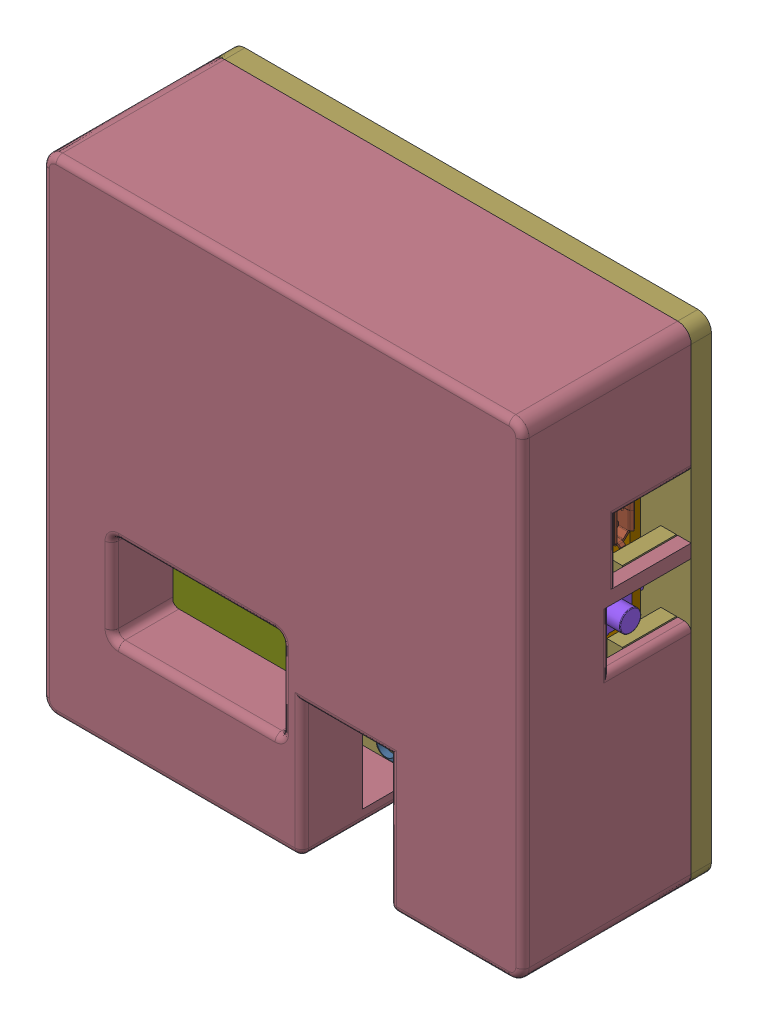
SolidWorks assembly Montagem Oximetro, configuration Valor predeterminado. Lengths in mm.
Overall size (71.15 72 28).
84 component instances, 29 part files, 20 mates.
Components (placement in the parent):
- ESP32-devkit_v1.step-1: ESP32-devkit_v1.step [Valor predeterminado] at (96.8522 -59.7162 9.78) x (0 -1 0) z (0 0 1) size (28.3 51.77 12.9)
  - ____________________ __________.step-1: ____________________ __________.step [Valor predeterminado] at origin size (27.94 38.1 11.2)
    - Body001.step-1: Body001.step [Valor predeterminado] at origin size (2.54 2.54 11.2)
    - Body001.step-2: Body001.step [Valor predeterminado] at (0 2.54 0) size (2.54 2.54 11.2)
    - Body001.step-3: Body001.step [Valor predeterminado] at (0 5.08 0) size (2.54 2.54 11.2)
    - Body001.step-4: Body001.step [Valor predeterminado] at (0 7.62 0) size (2.54 2.54 11.2)
    - Body001.step-5: Body001.step [Valor predeterminado] at (0 10.16 0) size (2.54 2.54 11.2)
    - Body001.step-6: Body001.step [Valor predeterminado] at (0 12.7 0) size (2.54 2.54 11.2)
    - Body001.step-7: Body001.step [Valor predeterminado] at (0 15.24 0) size (2.54 2.54 11.2)
    - Body001.step-8: Body001.step [Valor predeterminado] at (0 17.78 0) size (2.54 2.54 11.2)
    - Body001.step-9: Body001.step [Valor predeterminado] at (0 20.32 0) size (2.54 2.54 11.2)
    - Body001.step-10: Body001.step [Valor predeterminado] at (0 22.86 0) size (2.54 2.54 11.2)
    - Body001.step-11: Body001.step [Valor predeterminado] at (0 25.4 0) size (2.54 2.54 11.2)
    - Body001.step-12: Body001.step [Valor predeterminado] at (0 27.94 0) size (2.54 2.54 11.2)
    - Body001.step-13: Body001.step [Valor predeterminado] at (0 30.48 0) size (2.54 2.54 11.2)
    - Body001.step-14: Body001.step [Valor predeterminado] at (0 33.02 0) size (2.54 2.54 11.2)
    - Body001.step-15: Body001.step [Valor predeterminado] at (0 35.56 0) size (2.54 2.54 11.2)
    - Body001.step-16: Body001.step [Valor predeterminado] at (25.4 0 0) size (2.54 2.54 11.2)
    - Body001.step-17: Body001.step [Valor predeterminado] at (25.4 2.54 0) size (2.54 2.54 11.2)
    - Body001.step-18: Body001.step [Valor predeterminado] at (25.4 5.08 0) size (2.54 2.54 11.2)
    - Body001.step-19: Body001.step [Valor predeterminado] at (25.4 7.62 0) size (2.54 2.54 11.2)
    - Body001.step-20: Body001.step [Valor predeterminado] at (25.4 10.16 0) size (2.54 2.54 11.2)
    - Body001.step-21: Body001.step [Valor predeterminado] at (25.4 12.7 0) size (2.54 2.54 11.2)
    - Body001.step-22: Body001.step [Valor predeterminado] at (25.4 15.24 0) size (2.54 2.54 11.2)
    - Body001.step-23: Body001.step [Valor predeterminado] at (25.4 17.78 0) size (2.54 2.54 11.2)
    - Body001.step-24: Body001.step [Valor predeterminado] at (25.4 20.32 0) size (2.54 2.54 11.2)
    - Body001.step-25: Body001.step [Valor predeterminado] at (25.4 22.86 0) size (2.54 2.54 11.2)
    - Body001.step-26: Body001.step [Valor predeterminado] at (25.4 25.4 0) size (2.54 2.54 11.2)
    - Body001.step-27: Body001.step [Valor predeterminado] at (25.4 27.94 0) size (2.54 2.54 11.2)
    - Body001.step-28: Body001.step [Valor predeterminado] at (25.4 30.48 0) size (2.54 2.54 11.2)
    - Body001.step-29: Body001.step [Valor predeterminado] at (25.4 33.02 0) size (2.54 2.54 11.2)
    - Body001.step-30: Body001.step [Valor predeterminado] at (25.4 35.56 0) size (2.54 2.54 11.2)
  - ________________ __________.step-1: ________________ __________.step [Valor predeterminado] at origin size (28.3 51.2 1.6)
  - ESP32-WROOM-32.step-1: ESP32-WROOM-32.step [Valor predeterminado] at (14 15.8 1.6) x (-1 0 0) z (0 0 1) size (18 25.5 3.1)
  - USB_Micro-B_Molex_47346-0001.step-1: USB_Micro-B_Molex_47346-0001.step [Valor predeterminado] at (14 48 1.6) x (-1 0 0) z (0 0 1) size (7.98 5.42 2.97)
  - AMS-1117.step-1: AMS-1117.step [Valor predeterminado] at (19.5 39.6 1.6) size (7 6.5 1.7)
  - cp2102.step-1: cp2102.step [Valor predeterminado] at (8.2 39.5 1.6) x (-1 0 0) z (0 0 1) size (5 5 0.92)
  - SOT_23-1.step-1: SOT_23-1.step [Valor predeterminado] at (8 33.6 1.6) size (2.5 3 1.2)
  - SOT_23-2.step-1: SOT_23-2.step [Valor predeterminado] at (13.6 33.6 1.6) x (-1 0 0) z (0 0 1) size (2.5 3 1.2)
  - SW_SPST_B3U-1000P-1.step-1: SW_SPST_B3U-1000P-1.step [Valor predeterminado] at (6.2 48 1.6) x (0 1 0) z (0 0 1) size (4 2.51 1.59)
  - SW_SPST_B3U-1000P-2.step-1: SW_SPST_B3U-1000P-2.step [Valor predeterminado] at (22.2 48 1.6) x (0 1 0) z (0 0 1) size (4 2.51 1.59)
  - CP_EIA_3216_10_Kemet_I.step-1: CP_EIA_3216_10_Kemet_I.step [Valor predeterminado] at (21 34.2 1.6) x (-1 0 0) z (0 0 1) size (3.4 1.8 1.2)
- Case Montagem-1: Case Montagem [Valor predeterminado] at (126.0249 -86.5999 -4.5) x (1 0 0) z (0 -1 0) size (71.15 25 72)
  - Tampa Oximetro-1: Tampa Oximetro [Valor predeterminado] at origin size (71.15 11 72)
  - Case Oximetro-1: Case Oximetro [Valor predeterminado] at (0 25 0) x (1 0 0) z (0 0 -1) size (71.15 25 72)
  - IS - DIN985_M03×0.50-1: IS - DIN985_M03×0.50 [Valor predeterminado] at (-27.075 17.5 -0.5) size (6.08 4.25 5.5)
- pan head cross recess screw_iso-6: pan head cross recess screw_iso [ISO 7045 - M3 x 16 - Z - 16N] at (99.0249 -86.1024 -2.4) x (0 0 1) z (-1 0 0) size (18.35 5.6 5.6)
- pan head cross recess screw_iso-7: pan head cross recess screw_iso [ISO 7045 - M3 x 16 - Z - 16N] at (99.0249 -61.5924 -2.4) x (0 0 1) z (-1 0 0) size (18.35 5.6 5.6)
- pan head cross recess screw_iso-8: pan head cross recess screw_iso [ISO 7045 - M3 x 16 - Z - 16N] at (145.9749 -86.1024 -2.4) x (0 0 1) z (-1 0 0) size (18.35 5.6 5.6)
- pan head cross recess screw_iso-9: pan head cross recess screw_iso [ISO 7045 - M3 x 16 - Z - 16N] at (145.9749 -61.5924 -2.4) x (0 0 1) z (-1 0 0) size (18.35 5.6 5.6)
- 0.96 - IPS LCD - ST7735S.stp-1: 0.96 - IPS LCD - ST7735S.stp [Valor predeterminado] at (111.7844 -101.8949 9.78) size (31.02 24.13 4.17)
- pan head cross recess screw_iso-12: pan head cross recess screw_iso [ISO 7045 - M2 x 8 - Z - 8N] at (124.3955 -111.5215 8.18) x (0 0 1) z (-1 0 0) size (9.57 4 4)
- pan head cross recess screw_iso-13: pan head cross recess screw_iso [ISO 7045 - M2 x 8 - Z - 8N] at (99.1733 -111.5215 8.18) x (0 0 1) z (-1 0 0) size (9.57 4 4)
- pan head cross recess screw_iso-14: pan head cross recess screw_iso [ISO 7045 - M2 x 8 - Z - 8N] at (99.1733 -92.2683 8.18) x (0 0 1) z (-1 0 0) size (9.57 4 4)
- pan head cross recess screw_iso-15: pan head cross recess screw_iso [ISO 7045 - M2 x 8 - Z - 8N] at (124.3955 -92.2683 8.18) x (0 0 1) z (-1 0 0) size (9.57 4 4)
- hex thin nut chamfered gradeab_iso-4: hex thin nut chamfered gradeab_iso [ISO - 4035 - M2 - N] at (124.3955 -111.5215 13) x (0.866025 -0.5 0) z (0 0 -1) size (4 4.62 1.2)
- PCB_Oximetro.step-2: PCB_Oximetro.step [Valor predeterminado] at origin size (64.85 57.9 12.09)
  - CP_Radial_D5.0mm_P2.50mm.step-1: CP_Radial_D5.0mm_P2.50mm.step [Valor predeterminado] at (135.9499 -67.0499 1.63) size (6.13 6.52 7)
    - SOLID.step-1: SOLID.step [Valor predeterminado] at origin size (6.13 6.52 7)
  - PinSocket_1x08_P2.54mm_Vertical.step-1: PinSocket_1x08_P2.54mm_Vertical.step [Valor predeterminado] at (102.8999 -91.2999 1.63) x (0 1 0) z (0 0 1) size (2.54 20.32 10.1)
    - SOLID-0.step-1: SOLID-0.step [Valor predeterminado] at origin size (2.54 20.32 10.1)
  - SOT-223.step-1: SOT-223.step [Valor predeterminado] at (150.1499 -104.1999 1.63) x (0 -1 0) z (0 0 1) size (7 6.5 1.7)
    - SOLID-1.step-1: SOLID-1.step [Valor predeterminado] at origin size (7 6.5 1.7)
  - CP_Radial_Tantal_D5.0mm_P2.50mm.step-1: CP_Radial_Tantal_D5.0mm_P2.50mm.step [Valor predeterminado] at (148.9348 -110.8948 1.63) x (0 -1 0) z (0 0 1) size (5 5 10.1)
    - SOLID-2.step-1: SOLID-2.step [Valor predeterminado] at origin size (5 5 10.1)
  - CP_Radial_D5.0mm_P2.50mm.step-2: CP_Radial_D5.0mm_P2.50mm.step [Valor predeterminado] at (148.8999 -94.3499 1.63) size (6.13 6.52 7)
    - SOLID.step-1: SOLID.step [Valor predeterminado] at origin size (6.13 6.52 7)
  - R_1206_3216Metric.step-1: R_1206_3216Metric.step [Valor predeterminado] at (137.3499 -71.7999 1.63) size (3.2 1.6 0.55)
    - SOLID-3.step-1: SOLID-3.step [Valor predeterminado] at origin size (3.2 1.6 0.55)
  - PinSocket_1x05_P2.54mm_Vertical.step-1: PinSocket_1x05_P2.54mm_Vertical.step [Valor predeterminado] at (139.9999 -103.1999 1.63) x (0 -1 0) z (0 0 1) size (2.54 12.7 10.1)
    - SOLID-4.step-1: SOLID-4.step [Valor predeterminado] at origin size (2.54 12.7 10.1)
  - C_1206_3216Metric.step-1: C_1206_3216Metric.step [Valor predeterminado] at (153.2499 -111.1499 1.63) x (0 -1 0) z (0 0 1) size (3.2 1.6 1.6)
    - SOLID-5.step-1: SOLID-5.step [Valor predeterminado] at origin size (3.2 1.6 1.6)
  - C_1206_3216Metric.step-2: C_1206_3216Metric.step [Valor predeterminado] at (150.1499 -98.4999 1.63) size (3.2 1.6 1.6)
    - SOLID-5.step-1: SOLID-5.step [Valor predeterminado] at origin size (3.2 1.6 1.6)
  - D_DO-41_SOD81_P10.16mm_Horizontal.step-1: D_DO-41_SOD81_P10.16mm_Horizontal.step [Valor predeterminado] at (139.8199 -77.6999 1.63) size (10.96 2.72 5.71)
    - SOLID-6.step-1: SOLID-6.step [Valor predeterminado] at origin size (10.96 2.72 5.71)
  - SW_Tactile_SPST_Angled_PTS645Vx58-2LFS.step-1: SW_Tactile_SPST_Angled_PTS645Vx58-2LFS.step [Valor predeterminado] at (155.0374 -82.2249 1.63) x (0 -1 0) z (0 0 1) size (7.4 9.9 11)
    - SOLID-7.step-1: SOLID-7.step [Valor predeterminado] at origin size (7.4 9.9 11)
  - R_1206_3216Metric.step-2: R_1206_3216Metric.step [Valor predeterminado] at (149.3999 -83.7124 1.63) x (0 1 0) z (0 0 1) size (3.2 1.6 0.55)
    - SOLID-3.step-1: SOLID-3.step [Valor predeterminado] at origin size (3.2 1.6 0.55)
  - PCB.step-1: PCB.step [Valor predeterminado] at origin size (61.2 57.9 1.58)
- MAX30102-1: MAX30102 [Default] at (135.2675 -107.9442 10.38) x (1 0 0) z (0 -1 0) size (12 1.84 12)
- Micro USB 5 Pins, Right Angle SMT-1: Micro USB 5 Pins, Right Angle SMT [Default] at (157.0999 -73.6478 2.805) x (0 1 0) z (1 0 0) size (8.07 3.21 5.56)
Mates (geometry in assembly coordinates):
- Coincidente24: coincident: plane of ESP32-devkit_v1.step-1/________________ __________.step-1 through (122.4522 -73.8662 9.78) normal (0 0 -1); plane of 0.96 - IPS LCD - ST7735S.stp-1 through (111.7844 -101.8949 9.78) normal (0 0 -1)
- Concêntrico11: concentric anti-aligned: cylinder of 0.96 - IPS LCD - ST7735S.stp-1 through (124.3955 -111.5215 -27.6124) axis (0 0 1) radius 1.0922; cylinder of pan head cross recess screw_iso-12 through (124.3955 -111.5215 -17.22) axis (0 0 -1) radius 2
- Coincidente26: coincident anti-aligned: plane of 0.96 - IPS LCD - ST7735S.stp-1 through (111.7844 -101.8949 9.78) normal (0 0 -1); plane of pan head cross recess screw_iso-12 through (124.3955 -110.5215 9.78) normal (0 0 1)
- Concêntrico12: concentric anti-aligned: cylinder of 0.96 - IPS LCD - ST7735S.stp-1 through (99.1733 -111.5215 -27.6124) axis (0 0 1) radius 1.0922; cylinder of pan head cross recess screw_iso-13 through (99.1733 -111.5215 -17.22) axis (0 0 -1) radius 2
- Coincidente27: coincident anti-aligned: plane of 0.96 - IPS LCD - ST7735S.stp-1 through (111.7844 -101.8949 9.78) normal (0 0 -1); plane of pan head cross recess screw_iso-13 through (99.1733 -110.5215 9.78) normal (0 0 1)
- Concêntrico13: concentric anti-aligned: cylinder of 0.96 - IPS LCD - ST7735S.stp-1 through (99.1733 -92.2683 -27.6124) axis (0 0 1) radius 1.0922; cylinder of pan head cross recess screw_iso-14 through (99.1733 -92.2683 -17.22) axis (0 0 -1) radius 2
- Coincidente28: coincident anti-aligned: plane of 0.96 - IPS LCD - ST7735S.stp-1 through (111.7844 -101.8949 9.78) normal (0 0 -1); plane of pan head cross recess screw_iso-14 through (99.1733 -91.2683 9.78) normal (0 0 1)
- Concêntrico14: concentric anti-aligned: cylinder of 0.96 - IPS LCD - ST7735S.stp-1 through (124.3955 -92.2683 -27.6124) axis (0 0 1) radius 1.0922; cylinder of pan head cross recess screw_iso-15 through (124.3955 -92.2683 -17.22) axis (0 0 -1) radius 2
- Coincidente29: coincident anti-aligned: plane of 0.96 - IPS LCD - ST7735S.stp-1 through (111.7844 -101.8949 9.78) normal (0 0 -1); plane of pan head cross recess screw_iso-15 through (124.3955 -91.2683 9.78) normal (0 0 1)
- Concêntrico19: concentric aligned: cylinder of pan head cross recess screw_iso-12 through (124.3955 -111.5215 -17.22) axis (0 0 -1) radius 1; cylinder of hex thin nut chamfered gradeab_iso-4 through (124.3955 -111.5215 38.0375) axis (0 0 -1) radius 1
- Coincidente33: coincident aligned: plane of Case Montagem-1/Case Oximetro-1 through (126.0249 -86.5999 13) normal (0 0 -1); plane of hex thin nut chamfered gradeab_iso-4 through (123.2408 -113.5215 13) normal (0 0 -1)
- Paralelo5: parallel anti-aligned: plane of Case Montagem-1/Case Oximetro-1 through (126.7293 -111.4999 13) normal (-0.866025 0.5 0); plane of hex thin nut chamfered gradeab_iso-4 through (125.5502 -113.5215 14.2) normal (0.866025 -0.5 0)
- Coincidente34: coincident anti-aligned: plane of PCB_Oximetro.step-2/PCB.step-1 through (126.4999 -86.6499 1.58) normal (0 0 1); plane of Micro USB 5 Pins, Right Angle SMT-1 through (152.8999 -76.2649 1.58) normal (0 0 -1)
- Coincidente35: coincident aligned: line of PCB_Oximetro.step-2/PCB.step-1 through (157.0999 -57.6999 1.58) axis (0 -1 0); line of Micro USB 5 Pins, Right Angle SMT-1 through (157.0999 -71.0328 1.58) axis (0 -1 0)
- Concêntrico20: concentric aligned: circle of PCB_Oximetro.step-2/PCB.step-1; cylinder of MAX30102-1 through (137.4599 -103.1999 10.38) axis (0 0 1) radius 0.6025
- Coincidente37: coincident aligned: plane of ESP32-devkit_v1.step-1/________________ __________.step-1 through (122.4522 -73.8662 11.38) normal (0 0 1); plane of MAX30102-1 through (140.2675 -102.9442 11.38) normal (0 0 1)
- Paralelo6: parallel anti-aligned: line of PCB_Oximetro.step-2/PCB.step-1 through (157.0999 -115.5999 1.58) axis (-1 0 0); line of MAX30102-1 through (130.7675 -113.9442 11.38) axis (1 0 0)
- Coincidente39: coincident: plane of Case Montagem-1/Tampa Oximetro-1 through (157.0999 -118.0999 5) normal (-1 0 0); line of PCB_Oximetro.step-2/PCB.step-1 through (157.0999 -57.6999 1.58) axis (0 -1 0)
- Distância1: distance = 2.5 mm anti-aligned: plane of PCB_Oximetro.step-2/PCB.step-1 through (157.0999 -115.5999 0) normal (0 -1 0); plane of Case Montagem-1/Tampa Oximetro-1 through (94.9499 -118.0999 5) normal (0 1 0)
- Distância2: distance = 3 mm anti-aligned: plane of PCB_Oximetro.step-2/PCB.step-1 through (126.4999 -86.6499 0) normal (0 0 -1); plane of Case Montagem-1/Tampa Oximetro-1 through (126.0249 -86.5999 -3) normal (0 0 1)
